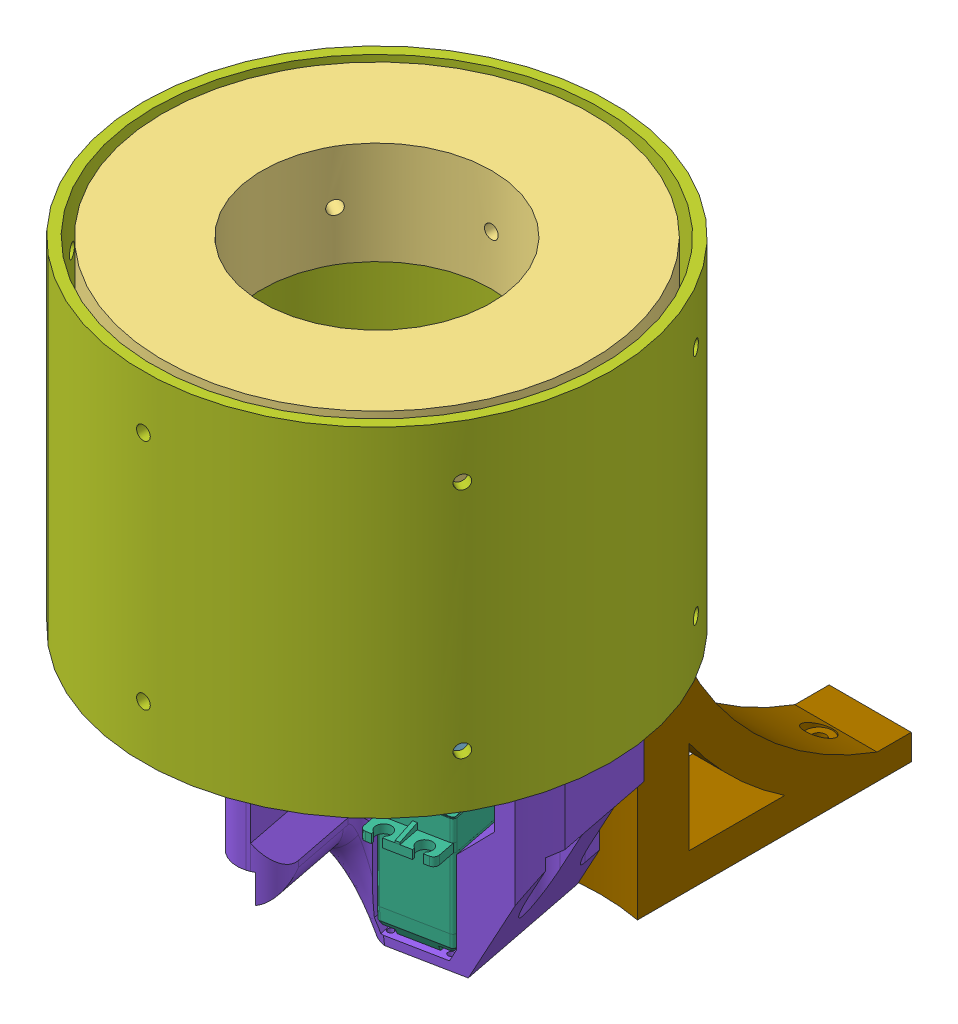
SolidWorks assembly Assembly, configuration Default. Lengths in mm.
Overall size (170.75 199 229.51).
37 component instances, 15 part files, 44 mates.
Components (placement in the parent):
- BottomRing-1: BottomRing [Default] at (51.7074 44.536 97.1539) size (125 30 125) (hidden)
- WheelBarNarrower-2: WheelBarNarrower [Default] at (3.8324 71.536 96.7811) x (0 -1 0) z (0 0 1) size (5.75 15 5.75)
- WheelEnlarged-2: WheelEnlarged [Default] at (9.0824 71.536 96.7811) x (0 -1 0) z (0 0 1) size (14.5 4.25 14.5)
- rotating portion-1: rotating portion [Default] at (51.7074 109.036 97.1539) x (-0.193408 0 -0.981118) z (0.981118 0 -0.193408) size (122.5 149.99 122.5) (hidden)
- TopRing-1: TopRing [Default] at (51.7074 143.536 97.1539) x (0.5 0 -0.866025) z (-0.866025 0 -0.5) size (125 30 125)
- Shaft-1: Shaft [Default] at (51.7074 97.536 97.1539) x (-0.981118 0 0.193408) z (0.193408 0 0.981118) size (35 68 46) (hidden)
- ShaftClamp-1: ShaftClamp [Default] at (51.7074 82.536 97.1539) x (0.193408 0 0.981118) z (0 -1 0) size (18.67 40.5 2.5)
- Gear-1: Gear [Default] at (51.7253 -48.301 99.2267) x (0 1 0) z (-0.258819 0 -0.965926) size (12.7 86.43 86.43) (hidden)
- ServoGear-1: ServoGear [Default] at (80.8782 43.536 91.4035) x (0.193408 0 0.981118) z (0 -1 0) size (34.67 34.67 10)
- ROBOT SERVO Hitec HSR-2645CR-1: ROBOT SERVO Hitec HSR-2645CR [По умолчанию] at (82.8123 -6.364 101.2147) x (-0.193408 0 -0.981118) z (0.981118 0 -0.193408) size (53.4 42.9 19.6)
- WheelEnlarged-6: WheelEnlarged [Default] at (30.7178 71.536 60.0532) x (0 -1 0) z (-0.866025 0 0.5) size (14.5 4.25 14.5) (hidden)
- WheelEnlarged-7: WheelEnlarged [Default] at (73.3428 71.536 60.426) x (0 -1 0) z (-0.866025 0 -0.5) size (14.5 4.25 14.5) (hidden)
- WheelEnlarged-8: WheelEnlarged [Default] at (94.3324 71.536 97.5267) x (0 -1 0) z (0 0 -1) size (14.5 4.25 14.5) (hidden)
- WheelEnlarged-9: WheelEnlarged [Default] at (72.6971 71.536 134.2547) x (0 -1 0) z (0.866025 0 -0.5) size (14.5 4.25 14.5) (hidden)
- WheelEnlarged-10: WheelEnlarged [Default] at (30.0721 71.536 133.8819) x (0 -1 0) z (0.866025 0 0.5) size (14.5 4.25 14.5) (hidden)
- WheelBarNarrower-3: WheelBarNarrower [Default] at (28.0928 71.536 55.5066) x (0 -1 0) z (-0.866025 0 0.5) size (5.75 15 5.75) (hidden)
- WheelBarNarrower-4: WheelBarNarrower [Default] at (75.9678 71.536 55.8794) x (0 -1 0) z (-0.866025 0 -0.5) size (5.75 15 5.75) (hidden)
- WheelBarNarrower-5: WheelBarNarrower [Default] at (99.5824 71.536 97.5267) x (0 -1 0) z (0 0 -1) size (5.75 15 5.75) (hidden)
- WheelBarNarrower-6: WheelBarNarrower [Default] at (75.3221 71.536 138.8013) x (0 -1 0) z (0.866025 0 -0.5) size (5.75 15 5.75) (hidden)
- WheelBarNarrower-7: WheelBarNarrower [Default] at (27.4471 71.536 138.4285) x (0 -1 0) z (0.866025 0 0.5) size (5.75 15 5.75) (hidden)
- WheelEnlarged-11: WheelEnlarged [Default] at (74.9623 116.661 57.1752) x (0.281851 -0.945558 0.162727) z (0.818877 0.325454 0.472779) size (14.5 4.25 14.5)
- WheelBarNarrower-8: WheelBarNarrower [Default] at (72.3373 116.661 61.7219) x (0.362886 0.907975 0.209512) z (-0.786329 0.419024 -0.453987) size (5.75 15 5.75)
- WheelEnlarged-12: WheelEnlarged [Default] at (97.9574 116.661 97.3039) x (0 -0.945558 0.325454) z (0 0.325454 0.945558) size (14.5 4.25 14.5)
- WheelEnlarged-13: WheelEnlarged [Default] at (74.7025 116.661 137.2826) x (-0.281851 -0.945558 0.162727) z (-0.818877 0.325454 0.472779) size (14.5 4.25 14.5)
- WheelEnlarged-14: WheelEnlarged [Default] at (28.4525 116.661 137.1326) x (-0.281851 -0.945558 -0.162727) z (-0.818877 0.325454 -0.472779) size (14.5 4.25 14.5)
- WheelEnlarged-15: WheelEnlarged [Default] at (5.4574 116.661 97.0039) x (0 -0.945558 -0.325454) z (0 0.325454 -0.945558) size (14.5 4.25 14.5)
- WheelEnlarged-16: WheelEnlarged [Default] at (28.7123 116.661 57.0252) x (0.281851 -0.945558 -0.162727) z (0.818877 0.325454 -0.472779) size (14.5 4.25 14.5)
- WheelBarNarrower-9: WheelBarNarrower [Default] at (92.7074 116.661 97.3039) x (0 0.907975 0.419024) z (0 0.419024 -0.907975) size (5.75 15 5.75)
- WheelBarNarrower-10: WheelBarNarrower [Default] at (72.0775 116.661 132.736) x (-0.362886 0.907975 0.209512) z (0.786329 0.419024 -0.453987) size (5.75 15 5.75)
- WheelBarNarrower-11: WheelBarNarrower [Default] at (31.0775 116.661 132.586) x (-0.362886 0.907975 -0.209512) z (0.786329 0.419024 0.453987) size (5.75 15 5.75)
- WheelBarNarrower-12: WheelBarNarrower [Default] at (10.7074 116.661 97.0039) x (0 0.907975 -0.419024) z (0 0.419024 0.907975) size (5.75 15 5.75)
- WheelBarNarrower-13: WheelBarNarrower [Default] at (31.3373 116.661 61.5719) x (0.362886 0.907975 -0.209512) z (-0.786329 0.419024 0.453987) size (5.75 15 5.75)
- Part4^Assembly-1: Part4^Assembly [Default] at (51.7074 44.536 97.1539) x (-1 0 0) z (0 -1 0) size (129 129 350) (hidden, virtual)
- Part5^Assembly-1: Part5^Assembly [Default] at (63.7954 143.536 158.4738) x (-0.981118 0 0.193408) z (-0.158431 0.573576 -0.803685) size (104 52 361.21) (hidden, virtual)
- BaseDrillGuide-1: BaseDrillGuide [Default] at (51.7074 44.536 97.1539) x (-1 0 0) z (0 -1 0) size (136.5 136.5 99)
- NewServoCarriage-2: NewServoCarriage [Default] at (78.8958 -6.364 81.347) x (-0.981118 0 0.193408) z (-0.193408 0 -0.981118) size (59.6 53.9 72.14)
- SorterStand-1: SorterStand [Default] at (51.7074 44.536 97.1539) x (-1 0 0) z (0 -1 0) size (24 86.06 125)
Mates (geometry in assembly coordinates):
- Concentric2: concentric: cylinder of WheelBarNarrower-2 through (18.8324 71.536 96.7811) axis (-1 0 0) radius 2.875; cylinder of WheelEnlarged-2 through (13.3324 71.536 96.7811) axis (-1 0 0) radius 3.5
- Distance3: distance = 5.5 mm: plane of WheelEnlarged-2 through (13.3324 71.536 96.7811) normal (1 0 0); plane of WheelBarNarrower-2 through (18.8324 71.536 96.7811) normal (1 0 0)
- Distance4: distance = 0.5 mm: plane of WheelBarNarrower-2 through (18.8324 71.536 96.7811) normal (1 0 0); plane of BottomRing-1 through (19.3324 68.536 100.5289) normal (-1 0 0)
- Concentric3: concentric: circle of BottomRing-1; circle of rotating portion-1
- Concentric6: concentric: circle of rotating portion-1; circle of TopRing-1
- Parallel2: parallel: cylinder of BottomRing-1 through (51.7074 60.036 129.6539) axis (0 0 1) radius 2; cylinder of TopRing-1 through (51.7074 128.036 182.5319) axis (0 0 -1) radius 2
- Distance5: distance = 4.5 mm: plane of rotating portion-1 through (51.7074 79.036 97.1539) normal (0 -1 0); plane of BottomRing-1 through (51.7074 74.536 97.1539) normal (0 1 0)
- Distance6: distance = 4.5 mm: plane of TopRing-1 through (51.7074 113.536 97.1539) normal (0 -1 0); plane of rotating portion-1 through (51.7074 109.036 97.1539) normal (0 1 0)
- Concentric10: concentric: circle of rotating portion-1; circle of Shaft-1
- Coincident3: coincident: plane of rotating portion-1 through (51.7074 109.036 97.1539) normal (0.981118 0 -0.193408); plane of Shaft-1 through (51.7074 97.536 97.1539) normal (-0.981118 0 0.193408)
- Distance7: distance = 0 mm: plane of rotating portion-1 through (68.5201 82.536 111.348) normal (0 -1 0); plane of Shaft-1 through (39.4966 82.536 116.6448) normal (0 -1 0)
- Concentric18: concentric: circle of WheelEnlarged-11; circle of WheelBarNarrower-8
- Distance9: distance = 5.5 mm: plane of WheelEnlarged-11 through (77.0873 116.661 53.4946) normal (0.5 0 -0.866025); plane of WheelBarNarrower-8 through (79.8373 116.661 48.7315) normal (0.5 0 -0.866025)
- Coincident24: coincident: plane of TopRing-1 through (82.6303 119.536 50.344) normal (-0.5 0 0.866025); plane of WheelBarNarrower-8 through (79.8373 116.661 48.7315) normal (0.5 0 -0.866025)
- Tangent12: tangent: plane of TopRing-1 through (51.7074 119.536 97.1539) normal (0 -1 0); cylinder of WheelBarNarrower-8 through (79.8373 116.661 48.7315) axis (-0.5 0 0.866025) radius 2.875
- Distance10: distance = 0.35 mm: plane of TopRing-1 through (74.6303 119.536 64.2004) normal (-0.866025 0 -0.5); cylinder of WheelBarNarrower-8 through (79.8373 116.661 48.7315) axis (-0.5 0 0.866025) radius 2.875
- InPlace5: in place: plane of ? through (-2.4191 143.536 65.9039) normal (0.709406 0.573576 0.409576); plane of ? through (-2.4191 143.536 65.9039) normal (0.709406 0.573576 0.409576); moOrthogonalPlaneRef_w of ? through (-2.4191 143.536 65.9039) normal (0.709406 0.573576 0.409576); plane of ? through (-2.4191 143.536 65.9039) normal (-0.496732 0.819152 -0.286788); plane of ? through (-2.4191 143.536 65.9039) normal (0.709406 0.573576 0.409576); plane of ? through (-2.4191 143.536 65.9039) normal (0.5 0 -0.866025); plane of rotating portion-1 through (63.7954 143.536 158.4738) normal (-0.158431 0.573576 -0.803685); unknown of Part5^Assembly-1
- Coincident28: coincident: plane of rotating portion-1; plane of Part5^Assembly-1
- Coincident29: coincident: moOrthogonalPlaneRef_w of rotating portion-1; plane of Part5^Assembly-1 through (63.7954 143.536 158.4738) normal (0.110934 0.819152 0.562746)
- Coincident30: coincident: moOrthogonalPlaneRef_w of rotating portion-1; plane of Part5^Assembly-1 through (63.7954 143.536 158.4738) normal (-0.981118 0 0.193408)
- InPlace6: in place: plane of ? through (51.7074 44.536 97.1539) normal (0 -1 0); plane of ? through (0 44.536 0) normal (0 -1 0); plane of ? through (51.7074 44.536 97.1539) normal (0 -1 0); plane of ? through (0 44.536 0) normal (0 0 -1); plane of ? through (51.7074 44.536 97.1539) normal (0 -1 0); plane of ? through (0 44.536 0) normal (-1 0 0); plane of ? through (51.7074 44.536 97.1539) normal (0 -1 0); unknown of ?
- Coincident32: coincident: plane of Part4^Assembly-1; plane of BaseDrillGuide-1
- Coincident33: coincident: moOrthogonalPlaneRef_w of Part4^Assembly-1 through (51.7074 44.536 97.1539) normal (0 0 -1); plane of BaseDrillGuide-1 through (51.7074 44.536 97.1539) normal (0 0 -1)
- Coincident34: coincident: moOrthogonalPlaneRef_w of Part4^Assembly-1 through (51.7074 44.536 97.1539) normal (1 0 0); plane of BaseDrillGuide-1 through (51.7074 44.536 97.1539) normal (-1 0 0)
- Distance11: distance = 30 mm: point of Shaft-1; point of ServoGear-1
- Concentric19: concentric: circle of rotating portion-1; circle of ShaftClamp-1
- Concentric20: concentric: circle of rotating portion-1; circle of ShaftClamp-1
- Parallel3: parallel: plane of Shaft-1 through (44.758 29.536 96.4858) normal (0 -1 0); plane of ServoGear-1 through (86.7855 43.536 95.1242) normal (0 1 0)
- Concentric21: concentric: circle of ServoGear-1; circle of ROBOT SERVO Hitec HSR-2645CR-1
- Coincident38: coincident: plane of ServoGear-1 through (80.8782 36.536 91.4035) normal (0 -1 0); plane of ROBOT SERVO Hitec HSR-2645CR-1 through (80.8782 36.536 91.4035) normal (0 1 0)
- Coincident41: coincident: plane of rotating portion-1 through (68.5201 82.536 111.348) normal (0 -1 0); plane of ShaftClamp-1 through (41.5394 82.536 116.6667) normal (0 1 0)
- Parallel6: parallel: line of ShaftClamp-1 through (55.2855 80.036 115.3046) axis (0.193408 0 0.981118); line of assembly
- Distance12: distance = 1 mm: plane of ServoGear-1 through (86.7855 43.536 95.1242) normal (0 1 0); plane of BottomRing-1 through (51.7074 44.536 97.1539) normal (0 -1 0)
- Parallel9: parallel: plane of ROBOT SERVO Hitec HSR-2645CR-1 through (77.1138 20.636 122.9777) normal (-0.981118 0 0.193408); line of assembly
- Perpendicular1: perpendicular: line of ShaftClamp-1 through (55.2855 80.036 115.3046) axis (0.193408 0 0.981118); line of ServoGear-1 through (80.8782 33.536 91.4035) axis (0.981118 0 -0.193408)
- Coincident55: coincident: line of ServoGear-1 through (80.8782 33.536 91.4035) axis (0.981118 0 -0.193408); plane of assembly
- InPlace7: in place: plane of ROBOT SERVO Hitec HSR-2645CR-1 through (69.2808 20.636 83.2424) normal (-0.193408 0 -0.981118); plane of ? through (18.3873 0 93.2751) normal (-0.193408 0 -0.981118); plane of ROBOT SERVO Hitec HSR-2645CR-1 through (69.2808 20.636 83.2424) normal (-0.193408 0 -0.981118); plane of ? through (18.3873 0 93.2751) normal (0 1 0); plane of ROBOT SERVO Hitec HSR-2645CR-1 through (69.2808 20.636 83.2424) normal (-0.193408 0 -0.981118); plane of ? through (18.3873 0 93.2751) normal (-0.981118 0 0.193408); plane of ROBOT SERVO Hitec HSR-2645CR-1 through (69.2808 20.636 83.2424) normal (-0.193408 0 -0.981118); unknown of NewServoCarriage-2
- Coincident56: coincident: plane of ROBOT SERVO Hitec HSR-2645CR-1; plane of NewServoCarriage-2
- Coincident57: coincident: moOrthogonalPlaneRef_w of ROBOT SERVO Hitec HSR-2645CR-1 through (78.8958 -6.364 81.347) normal (0 1 0); plane of NewServoCarriage-2 through (78.8958 -6.364 81.347) normal (0 1 0)
- Coincident58: coincident: moOrthogonalPlaneRef_w of ROBOT SERVO Hitec HSR-2645CR-1 through (78.8958 -6.364 81.347) normal (0.981118 0 -0.193408); plane of NewServoCarriage-2 through (78.8958 -6.364 81.347) normal (-0.981118 0 0.193408)
- InPlace8: in place: plane of ? through (51.7074 44.536 97.1539) normal (0 -1 0); plane of ? through (0 44.536 0) normal (0 -1 0); plane of ? through (51.7074 44.536 97.1539) normal (0 -1 0); plane of ? through (0 44.536 0) normal (0 0 -1); plane of ? through (51.7074 44.536 97.1539) normal (0 -1 0); plane of ? through (0 44.536 0) normal (-1 0 0); plane of ? through (51.7074 44.536 97.1539) normal (0 -1 0); unknown of ?
- Coincident56: coincident: plane of BaseDrillGuide-1; plane of SorterStand-1
- Coincident57: coincident: moOrthogonalPlaneRef_w of BaseDrillGuide-1 through (51.7074 44.536 97.1539) normal (0 0 -1); plane of SorterStand-1 through (51.7074 44.536 97.1539) normal (0 0 -1)
- Coincident58: coincident: moOrthogonalPlaneRef_w of BaseDrillGuide-1 through (51.7074 44.536 97.1539) normal (1 0 0); plane of SorterStand-1 through (51.7074 44.536 97.1539) normal (-1 0 0)
